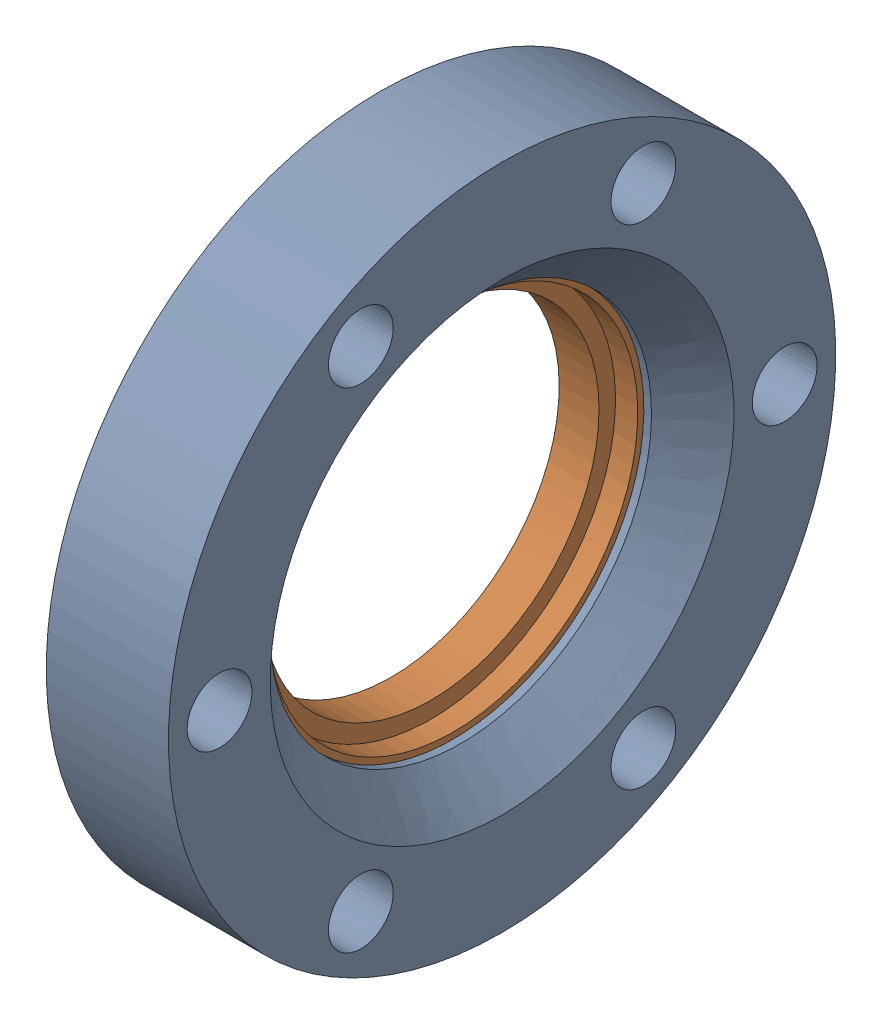
SolidWorks assembly 404002 P2_100014 (2.75 X 1.5 R), configuration Default. Lengths in mm.
Overall size (12.7 69.34 69.34).
2 component instances, 2 part files, 0 mates.
Components (placement in the parent):
- 404002 P3_100014 (2.75 X 1.5 REC)-1: 404002 P3_100014 (2.75 X 1.5 REC) [Default] at origin size (12.7 69.34 69.34)
- 404002 P1_100014 (2.75 X 1.5 INS)-1: 404002 P1_100014 (2.75 X 1.5 INS) [Default] at (1.17 0 0) x (1 0 0) z (0 0.994423 -0.105464) size (6.96 48.1 48.1)
